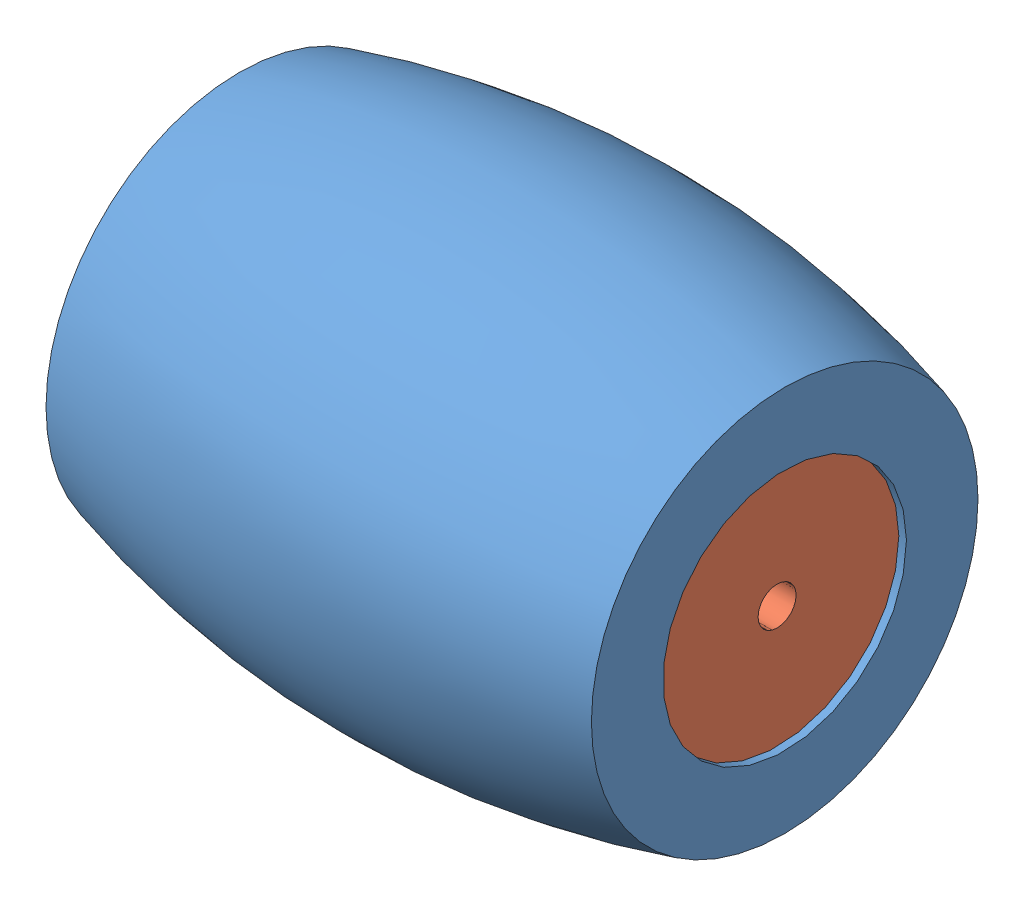
SolidWorks assembly Roller coated, configuration Default. Lengths in mm.
Overall size (35.83 30.44 30.44).
2 component instances, 2 part files, 6 mates.
Components (placement in the parent):
- Roller coating 12-1: Roller coating 12 [Default] at origin size (35.83 30.44 30.44)
- Roller core 12 coated-1: Roller core 12 coated [Default] at origin size (34.83 29.44 29.44)
Mates (geometry in assembly coordinates):
- Coincident1: coincident aligned: plane of Roller coating 12-1 through (17.3295 0 0) normal (0 0 1)
- Coincident2: coincident aligned: plane of Roller coating 12-1 through (17.3295 0 0) normal (0 1 0)
- Coincident3: coincident aligned: plane of Roller coating 12-1 through (0 0 0) normal (1 0 0)
- Coincident4: coincident aligned: plane of Roller core 12 coated-1 through (-11.4557 0 0) normal (0 0 1)
- Coincident5: coincident aligned: plane of Roller core 12 coated-1 through (-11.4557 0 0) normal (0 1 0)
- Coincident6: coincident aligned: plane of Roller core 12 coated-1 through (0 0 0) normal (1 0 0)
